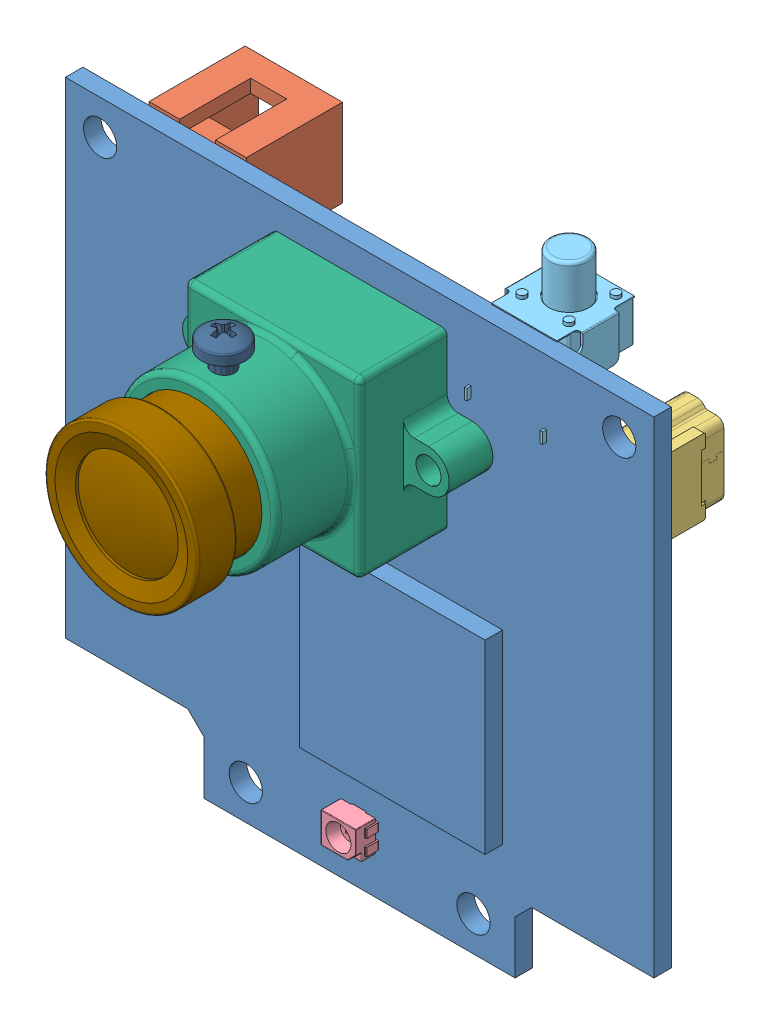
SolidWorks assembly Pixy(CMUcam5), configuration rev1.3. Lengths in mm.
Overall size (53.85 54.8 33.85).
10 component instances, 10 part files, 28 mates.
Components (placement in the parent):
- Pixy_board-1: Pixy_board [rev1.3] at origin size (53.85 50.8 3.2)
- header_2x5ways-1: header_2x5ways [Default] at (-18.024 -0.91 -1.4) x (0 1 0) z (0 0 -1) size (20.3 10 10.4)
- mini_usb_b_vertical_connector-1: mini_usb_b_vertical_connector [Défaut] at (20.324 -0.785 -9.4) x (0 -1 0) z (0 0 -1) size (7.7 4.7 9.8)
- RGB_led_CMS-1: RGB_led_CMS [STD] at (0 -35.26 1.6) x (1 0 0) z (0 -1 0) size (3.5 1.95 2.8)
- switch-FSMRA6JH-1: switch-FSMRA6JH [Défaut] at (13.549 10.54 -4.01) x (-1 0 0) z (0 0 -1) size (7.11 10.9 8.99)
- M12_lens_holder-1: M12_lens_holder [Défaut] at (0 0 1.6) size (24.4 16 15)
- header3x2-1: header3x2 [Défaut] at (-14.924 -22.91 -2) x (1 0 0) z (0 1 0) size (8 10.45 7.62)
- header_MTA-100_2pins-1: header_MTA-100_2pins [Défaut] at (-14.924 -30.56 -2.54) x (1 0 0) z (0 0 -1) size (5.08 5.84 10.03)
- pixy_lens-1: pixy_lens [Défaut] at (0 0 6.4) x (0.989146 0.146935 0) z (0.146935 -0.989146 0) size (14 17 14)
- pan head cross recess screw_iso-1: pan head cross recess screw_iso [ISO 7045 - M2 x 4 - Z --- 4C] at (0 10.3386 14.06) x (0 -1 0) z (0.040708 0 0.999171) size (5.57 4 4)
Mates (geometry in assembly coordinates):
- Coincident1: coincident aligned: plane of Pixy_board-1 through (0 0 0) normal (0 0 1); plane of header_2x5ways-1 through (-22.724 -11.06 0) normal (0 0 1)
- Parallel2: parallel anti-aligned: plane of header_2x5ways-1 through (-22.474 -11.06 -1.6) normal (-1 0 0); plane of Pixy_board-1 through (0 0 0) normal (1 0 0)
- Coincident5: coincident: plane of assembly; point of Pixy_board-1; plane of header_2x5ways-1 through (-18.024 -0.91 -1.4) normal (1 0 0)
- Coincident6: coincident: plane of assembly; point of Pixy_board-1; plane of header_2x5ways-1 through (-18.024 -0.91 -1.4) normal (0 1 0)
- Coincident7: coincident anti-aligned: plane of mini_usb_b_vertical_connector-1 through (20.324 -0.785 0) normal (0 0 -1)
- Coincident8: coincident: plane of assembly; point of Pixy_board-1; plane of mini_usb_b_vertical_connector-1 through (20.324 -0.785 -9.4) normal (-1 0 0)
- Coincident9: coincident: plane of assembly; point of Pixy_board-1; plane of mini_usb_b_vertical_connector-1 through (20.324 -0.785 -9.4) normal (0 -1 0)
- Parallel3: parallel anti-aligned: plane of mini_usb_b_vertical_connector-1 through (20.324 -0.785 -9.4) normal (-1 0 0)
- Coincident11: coincident aligned: plane of Pixy_board-1 through (0 0 1.6) normal (0 0 1); plane of RGB_led_CMS-1 through (0 -35.26 1.6) normal (0 0 1)
- Coincident12: coincident: plane of assembly; point of Pixy_board-1; plane of RGB_led_CMS-1 through (0 -35.26 1.6) normal (1 0 0)
- Coincident13: coincident: plane of assembly; point of Pixy_board-1; plane of RGB_led_CMS-1 through (0 -35.26 1.6) normal (0 -1 0)
- Parallel4: parallel aligned: plane of Pixy_board-1 through (0 0 0) normal (1 0 0); plane of RGB_led_CMS-1 through (0 -35.26 1.6) normal (1 0 0)
- Coincident15: coincident anti-aligned: plane of Pixy_board-1 through (0 0 0) normal (0 0 1); plane of switch-FSMRA6JH-1 through (13.549 10.54 0) normal (0 0 -1)
- Coincident16: coincident aligned: plane of Pixy_board-1 through (26.924 10.54 75.6287) normal (0 1 0); plane of switch-FSMRA6JH-1 through (13.549 10.54 -4.01) normal (0 1 0)
- Coincident17: coincident: plane of assembly; point of Pixy_board-1; plane of switch-FSMRA6JH-1 through (13.549 10.54 -4.01) normal (-1 0 0)
- Coincident21: coincident aligned: plane of Pixy_board-1 through (0 0 1.6) normal (0 0 1); plane of M12_lens_holder-1 through (0 0 1.6) normal (0 0 1)
- Coincident22: coincident aligned: plane of Pixy_board-1 through (0 0 0) normal (0 1 0); plane of M12_lens_holder-1 through (0 0 1.6) normal (0 1 0)
- Coincident23: coincident aligned: plane of M12_lens_holder-1 through (0 0 1.6) normal (1 0 0)
- Coincident24: coincident anti-aligned: plane of Pixy_board-1 through (0 0 0) normal (0 0 1); plane of header3x2-1 through (-14.924 -22.91 0) normal (0 0 -1)
- Coincident25: coincident: plane of assembly; point of Pixy_board-1; plane of header3x2-1 through (-14.924 -22.91 -2) normal (0 1 0)
- Coincident27: coincident: plane of assembly; point of Pixy_board-1; plane of header3x2-1 through (-14.924 -22.91 -2) normal (1 0 0)
- Coincident28: coincident anti-aligned: plane of Pixy_board-1 through (0 0 0) normal (0 0 1); plane of header_MTA-100_2pins-1 through (-14.924 -30.56 0) normal (0 0 -1)
- Coincident29: coincident: plane of assembly; point of Pixy_board-1; plane of header_MTA-100_2pins-1 through (-14.924 -30.56 -2.54) normal (1 0 0)
- Coincident30: coincident: plane of assembly; point of Pixy_board-1; plane of header_MTA-100_2pins-1 through (-14.924 -30.56 -2.54) normal (0 -1 0)
- Parallel5: parallel aligned: plane of Pixy_board-1 through (0 0 0) normal (1 0 0); plane of header_MTA-100_2pins-1 through (-14.924 -30.56 -2.54) normal (1 0 0)
- Concentric1: concentric anti-aligned: cylinder of M12_lens_holder-1 through (0 0 16.6) axis (0 0 -1) radius 6.05; cylinder of pixy_lens-1 through (0 0 27.0365) axis (0 0 1) radius 6
- Distance1: distance = 23.4 mm anti-aligned: plane of pixy_lens-1 through (1.0285 -6.924 23.4) normal (0 0 1); plane of Pixy_board-1 through (0 0 0) normal (0 0 -1)
- Concentric4: concentric anti-aligned: cylinder of M12_lens_holder-1 through (0 8 14.06) axis (0 -1 0) radius 1; cylinder of pan head cross recess screw_iso-1 through (0 35.7386 14.06) axis (0 1 0) radius 1
